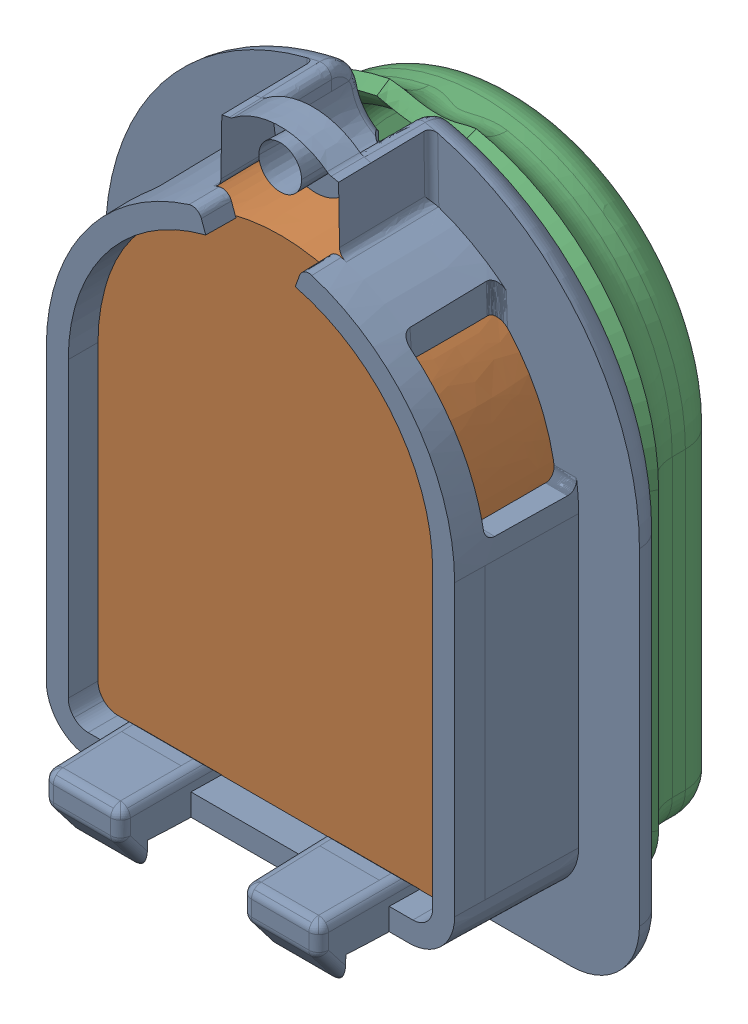
SolidWorks assembly C2(2), configuration 默认. Lengths in mm.
Overall size (26.95 34.26 17.16).
5 component instances, 5 part files, 0 mates.
Components (placement in the parent):
- Tip-1: Tip [默认] at origin size (26.95 34.26 11.17)
- Lens-1: Lens [默认] at origin size (18.59 25.47 6.15)
- Skin1-1: Skin1 [默认] x (-1 0 0) z (0 0 -1) size (22.77 29.32 5.25)
- Digit_coordinate_marker1-1: Digit_coordinate_marker1 [默认] at (0 0 -6.5) size (14 20 0.5)
- Digit_coordinate_marker2-1: Digit_coordinate_marker2 [默认] at (0 0 -3.25) size (12.5 18.5 2)
